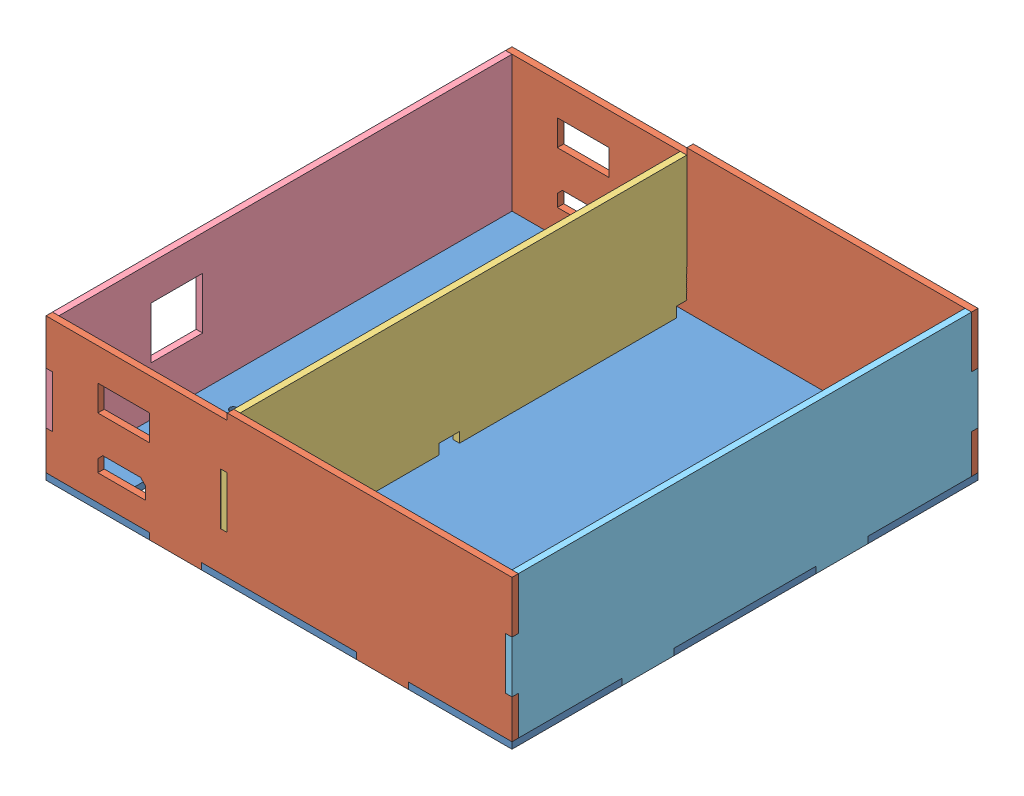
SolidWorks assembly Assembled, configuration Default. Lengths in mm.
Overall size (228.6 73.02 228.6).
7 component instances, 6 part files, 6 mates.
Components (placement in the parent):
- CellBack-1: CellBack [Default] at (21.2998 -14.7421 -1.224) size (228.6 3.17 228.6)
- CellTopBottom-1: CellTopBottom [Default] at (21.2998 23.3579 -115.524) size (228.6 73.03 3.17)
- CellTopBottom-2: CellTopBottom [Default] at (21.2998 23.3579 109.901) size (228.6 73.03 3.17)
- CellCenter-1: CellCenter [Default] at (-7.2752 24.4489 4.1169) size (3.17 69.85 228.6)
- CellLeft-1: CellLeft [Default] at (-93.0002 31.2039 -6.759) size (3.17 69.85 228.6)
- CellRight-1: CellRight [Default] at (132.4248 31.2039 -6.759) size (3.17 73.02 228.6)
- CellFront-1: CellFront [Default] at (-56.063 55.1079 -85.4184) size (88.9 3.17 228.6) (hidden)
Mates (geometry in assembly coordinates):
- Coincident1: coincident: point of CellBack-1; point of CellTopBottom-2
- Coincident3: coincident: point of CellBack-1; point of CellTopBottom-1
- Coincident5: coincident: point of CellBack-1; point of CellCenter-1
- Coincident8: coincident: point of CellTopBottom-2; point of CellLeft-1
- Coincident9: coincident: point of CellTopBottom-2; point of CellRight-1
- Coincident10: coincident: point of CellTopBottom-2; point of CellFront-1
